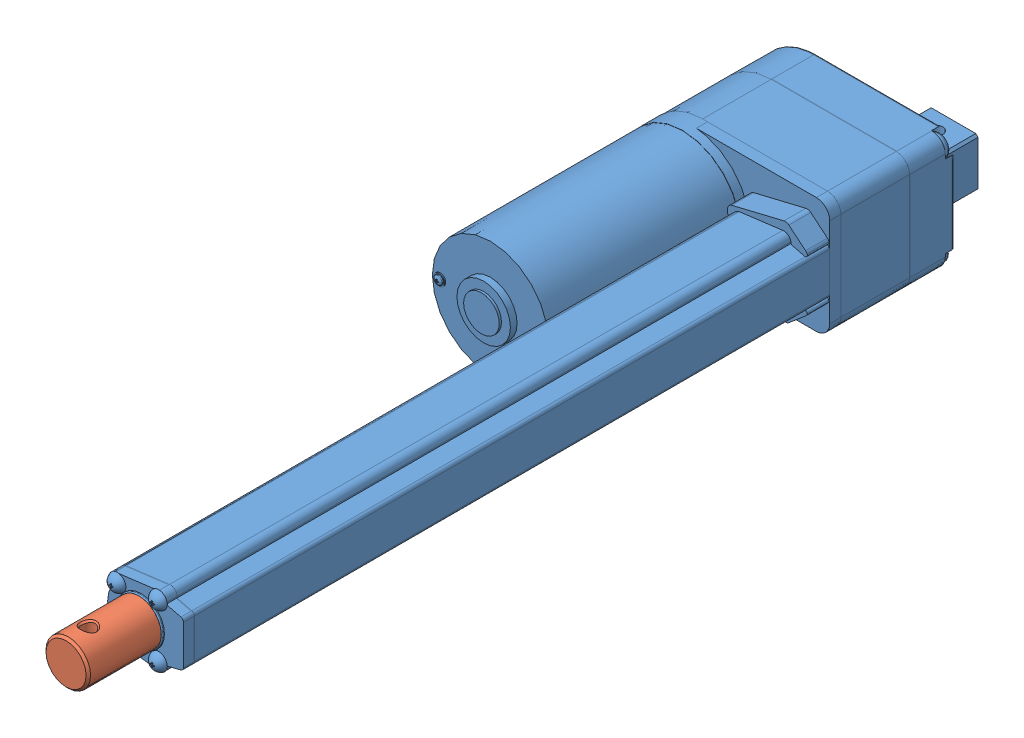
SolidWorks assembly FA-OS-400-12-9, configuration Default. Lengths in mm.
Overall size (88.18 52.2 398.91).
2 component instances, 2 part files, 6 mates.
Components (placement in the parent):
- FA-OS-400-12-9 BASE-1: FA-OS-400-12-9 BASE [Default] at origin size (88.18 52.2 368.11)
- FA-OS-400-12-9 ROD-1: FA-OS-400-12-9 ROD [Default] at (36 0 199.6043) x (0 -1 0) z (-1 0 0) size (19.99 304.8 19.99)
Mates (geometry in assembly coordinates):
- Concentric1: concentric anti-aligned: cylinder of FA-OS-400-12-9 BASE-1 through (36 0 92.0291) axis (0 0 1) radius 10; cylinder of FA-OS-400-12-9 ROD-1 through (36 0 352.0043) axis (0 0 -1) radius 9.9949
- Coincident1: coincident aligned: plane of FA-OS-400-12-9 BASE-1 through (0 0 0) normal (0 0 1)
- Coincident2: coincident aligned: plane of FA-OS-400-12-9 BASE-1 through (0 0 0) normal (0 1 0)
- Coincident3: coincident aligned: plane of FA-OS-400-12-9 BASE-1 through (0 0 0) normal (1 0 0)
- Parallel1: parallel anti-aligned: cylinder of FA-OS-400-12-9 BASE-1 through (35 12 -39) axis (0 -1 0) radius 3; cylinder of FA-OS-400-12-9 ROD-1 through (36 9.9949 342.0043) axis (0 1 0) radius 3
- LimitDistance1: limit distance = 375.0056 mm: cylinder of FA-OS-400-12-9 BASE-1 through (35 12 -39) axis (0 -1 0) radius 3; cylinder of FA-OS-400-12-9 ROD-1 through (36 9.9949 342.0043) axis (0 1 0) radius 3
